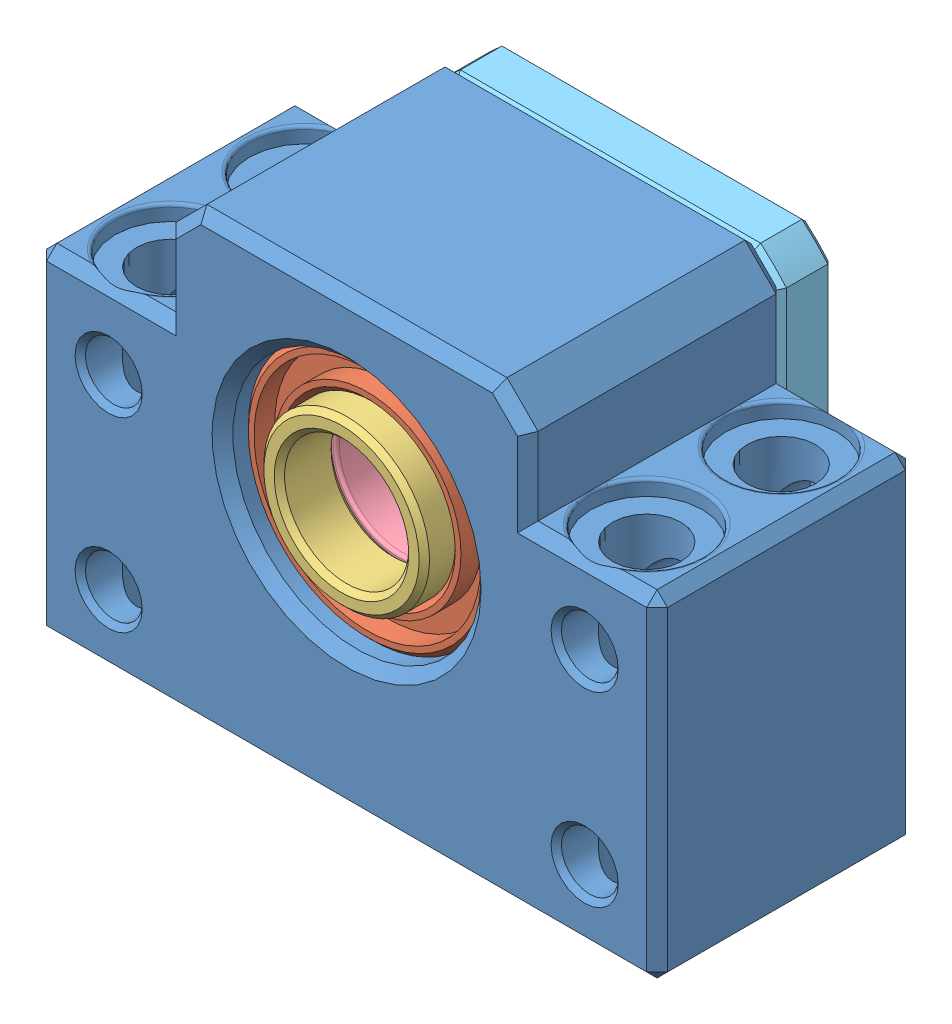
SolidWorks assembly BK12, configuration Default. Lengths in mm.
Overall size (60 43 35.16).
15 component instances, 8 part files, 30 mates.
Components (placement in the parent):
- BK12-1-1: BK12-1 [Default] at (-11.028 26.197 -11.9785) size (60 43 25)
- BK12-2-5: BK12-2 [Default] at (-11.028 8.197 8.0215) size (24 24 3)
- BK12-3-4: BK12-3 [Default] at (-11.028 8.197 8.0215) size (16 16 5.5)
- 6001-Bearing-3: 6001-Bearing [Default] at (-11.028 8.197 0.0215) size (28 28 8)
- 6001-Bearing-4: 6001-Bearing [Default] at (-11.028 8.197 -7.9785) size (28 28 8)
- BK12-2-6: BK12-2 [Default] at (-11.028 8.197 -7.9785) x (-1 0 0) z (0 0 -1) size (24 24 3)
- BK12-3-5: BK12-3 [Default] at (-11.028 8.197 -13.4785) size (16 16 5.5)
- BK12-4-1: BK12-4 [Default] at (-11.028 8.197 -16.9785) size (34 34 9)
- socket head cap screw_din-2: socket head cap screw_din [DIN 912 M3 x 8 --- 8N] at (-22.878 20.047 -16.9785) x (0 0 1) z (-1 0 0) size (11 5.5 5.5)
- socket head cap screw_din-3: socket head cap screw_din [DIN 912 M3 x 8 --- 8N] at (-22.878 -3.653 -16.9785) x (0 0 1) z (-1 0 0) size (11 5.5 5.5)
- socket head cap screw_din-4: socket head cap screw_din [DIN 912 M3 x 8 --- 8N] at (0.822 20.047 -16.9785) x (0 0 1) z (-1 0 0) size (11 5.5 5.5)
- socket head cap screw_din-5: socket head cap screw_din [DIN 912 M3 x 8 --- 8N] at (0.822 -3.653 -16.9785) x (0 0 1) z (-1 0 0) size (11 5.5 5.5)
- BK12-5-1: BK12-5 [Default] at (-11.028 8.197 -21.4785) size (19 19 8.53)
- socket set screw cup point_din-18: socket set screw cup point_din [DIN 916 - M3 x 4-N] at (-3.3011 15.9239 -18.7785) x (-0.707107 -0.707107 0) z (-0.70706 0.70706 -0.011443) size (4 3 3)
- socket set screw cup point_din-19: socket set screw cup point_din [DIN 916 - M3 x 4-N] at (-18.7549 15.9239 -18.7785) x (0.707107 -0.707107 0) z (0 0 1) size (4 3 3)
Mates (geometry in assembly coordinates):
- Concentric12: concentric aligned: cylinder of BK12-2-5 through (-11.028 8.197 11.0215) axis (0 0 -1) radius 8; cylinder of BK12-3-4 through (-11.028 8.197 13.5215) axis (0 0 -1) radius 8
- Coincident10: coincident aligned: plane of BK12-2-5 through (-11.028 8.197 8.0215) normal (0 0 -1); plane of BK12-3-4 through (-11.028 8.197 8.0215) normal (0 0 -1)
- Concentric13: concentric aligned: cylinder of BK12-1-1 through (-11.028 8.197 13.0215) axis (0 0 -1) radius 12; cylinder of BK12-2-5 through (-11.028 8.197 11.0215) axis (0 0 -1) radius 12
- Coincident11: coincident aligned: plane of BK12-1-1 through (-11.028 8.197 8.0215) normal (0 0 -1); plane of BK12-2-5 through (-11.028 8.197 8.0215) normal (0 0 -1)
- Concentric14: concentric aligned: cylinder of BK12-1-1 through (-11.028 8.197 8.0215) axis (0 0 -1) radius 14; cylinder of 6001-Bearing-3 through (-11.028 8.197 8.0215) axis (0 0 -1) radius 14
- Coincident12: coincident anti-aligned: plane of BK12-1-1 through (-11.028 8.197 8.0215) normal (0 0 -1); plane of 6001-Bearing-3 through (-11.028 8.197 8.0215) normal (0 0 1)
- Concentric15: concentric aligned: cylinder of BK12-1-1 through (-11.028 8.197 8.0215) axis (0 0 -1) radius 14; cylinder of 6001-Bearing-4 through (-11.028 8.197 0.0215) axis (0 0 -1) radius 14
- Coincident13: coincident anti-aligned: plane of 6001-Bearing-3 through (-11.028 8.197 0.0215) normal (0 0 -1); plane of 6001-Bearing-4 through (-11.028 8.197 0.0215) normal (0 0 1)
- Concentric16: concentric anti-aligned: cylinder of BK12-2-6 through (-11.028 8.197 -10.9785) axis (0 0 1) radius 8; cylinder of BK12-3-5 through (-11.028 8.197 -7.9785) axis (0 0 -1) radius 8
- Coincident14: coincident aligned: plane of BK12-2-6 through (-11.028 8.197 -7.9785) normal (0 0 1); plane of BK12-3-5 through (-11.028 8.197 -7.9785) normal (0 0 1)
- Concentric17: concentric anti-aligned: cylinder of BK12-1-1 through (-11.028 8.197 8.0215) axis (0 0 -1) radius 14; cylinder of BK12-2-6 through (-11.028 8.197 -10.9785) axis (0 0 1) radius 12
- Coincident15: coincident anti-aligned: plane of 6001-Bearing-4 through (-11.028 8.197 -7.9785) normal (0 0 -1); plane of BK12-2-6 through (-11.028 8.197 -7.9785) normal (0 0 1)
- Concentric18: concentric anti-aligned: cylinder of BK12-1-1 through (-11.028 8.197 8.0215) axis (0 0 -1) radius 14; cylinder of BK12-4-1 through (-11.028 8.197 -11.9785) axis (0 0 1) radius 14
- Angle1: planar angle = 0 rad aligned: plane of BK12-4-1 through (-25.528 25.197 -7.9785) normal (0 1 0); plane of BK12-1-1 through (6.472 26.197 13.0215) normal (0 1 0)
- Coincident17: coincident anti-aligned: plane of BK12-1-1 through (18.972 -16.803 -11.9785) normal (0 0 -1); plane of BK12-4-1 through (-11.028 8.197 -11.9785) normal (0 0 1)
- Concentric19: concentric aligned: cylinder of BK12-4-1 through (-22.878 20.047 -7.9785) axis (0 0 -1) radius 1.5; cylinder of socket head cap screw_din-2 through (-22.878 20.047 -48.7285) axis (0 0 -1) radius 1.5
- Coincident18: coincident anti-aligned: plane of BK12-4-1 through (-22.878 20.047 -13.9785) normal (0 0 -1); plane of socket head cap screw_din-2 through (-22.878 22.797 -13.9785) normal (0 0 1)
- Concentric20: concentric aligned: cylinder of BK12-4-1 through (-22.878 -3.653 -13.9785) axis (0 0 -1) radius 4; cylinder of socket head cap screw_din-3 through (-22.878 -3.653 -48.7285) axis (0 0 -1) radius 2.75
- Coincident19: coincident anti-aligned: plane of BK12-4-1 through (-22.878 -3.653 -13.9785) normal (0 0 -1); plane of socket head cap screw_din-3 through (-22.878 -0.903 -13.9785) normal (0 0 1)
- Concentric21: concentric aligned: cylinder of BK12-4-1 through (0.822 20.047 -7.9785) axis (0 0 -1) radius 1.5; cylinder of socket head cap screw_din-4 through (0.822 20.047 -48.7285) axis (0 0 -1) radius 2.75
- Coincident20: coincident anti-aligned: plane of BK12-4-1 through (0.822 20.047 -13.9785) normal (0 0 -1); plane of socket head cap screw_din-4 through (0.822 22.797 -13.9785) normal (0 0 1)
- Concentric22: concentric aligned: cylinder of BK12-4-1 through (0.822 -3.653 -13.9785) axis (0 0 -1) radius 4; cylinder of socket head cap screw_din-5 through (0.822 -3.653 -48.7285) axis (0 0 -1) radius 2.75
- Coincident21: coincident anti-aligned: plane of BK12-4-1 through (0.822 -3.653 -13.9785) normal (0 0 -1); plane of socket head cap screw_din-5 through (0.822 -0.903 -13.9785) normal (0 0 1)
- Coincident22: coincident anti-aligned: plane of BK12-3-5 through (-11.028 8.197 -13.4785) normal (0 0 -1); plane of BK12-5-1 through (-11.028 8.197 -13.4785) normal (0 0 1)
- Concentric23: concentric anti-aligned: circle of BK12-3-5; circle of BK12-5-1
- Concentric35: concentric anti-aligned: cylinder of BK12-5-1 through (-20.529 17.698 -18.7785) axis (0.707107 -0.707107 0) radius 1.5; cylinder of socket set screw cup point_din-19 through (-27.7351 24.9041 -18.7785) axis (-0.707107 0.707107 0) radius 1.5
- Tangent3: tangent aligned: cylinder of BK12-5-1 through (-11.028 8.197 -13.4785) axis (0 0 -1) radius 10.9275; plane of socket set screw cup point_din-19 through (-18.7549 15.9239 -18.7785) normal (-0.707107 0.707107 0)
- Concentric36: concentric anti-aligned: cylinder of BK12-5-1 through (-1.527 17.698 -18.7785) axis (-0.707107 -0.707107 0) radius 1.5; cylinder of socket set screw cup point_din-18 through (5.6792 24.9041 -18.7785) axis (0.707107 0.707107 0) radius 1.5
- Tangent4: tangent aligned: cylinder of BK12-5-1 through (-11.028 8.197 -13.4785) axis (0 0 -1) radius 10.9275; plane of socket set screw cup point_din-18 through (-3.3011 15.9239 -18.7785) normal (0.707107 0.707107 0)
- Angle2: planar angle = 0 rad aligned: plane of BK12-5-1 through (-16.428 17.697 -13.4785) normal (0 1 0); plane of BK12-4-1 through (-25.528 25.197 -7.9785) normal (0 1 0)
